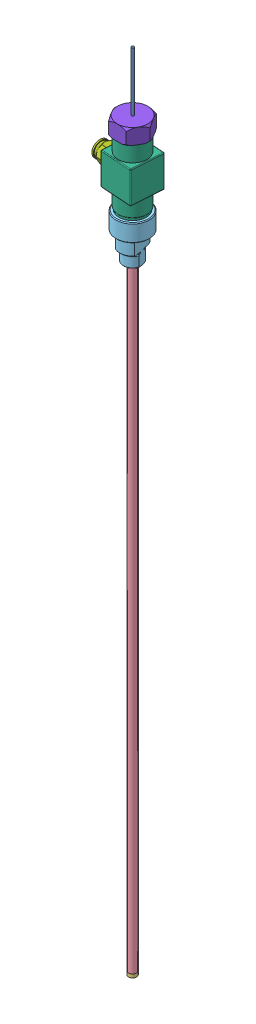
SolidWorks assembly Ensamblaje de Pipeta-Tee-Conectores, configuration Predeterminado. Lengths in mm.
Overall size (68.97 1003.7 49.84).
8 component instances, 8 part files, 12 mates.
Components (placement in the parent):
- Varilla de la pipeta-1: Varilla de la pipeta [Predeterminado] at (-128.4061 644.2501 1001.5875) size (3.17 1003.7 3.17)
- Buje interior del pico-1: Buje interior del pico [Predeterminado] at (-128.4061 -347.3121 1001.5875) x (0.891914 0 0.452205) z (-0.452205 0 0.891914) size (6 4 6)
- Pico de la Pipeta-1: Pico de la Pipeta [Predeterminado] at (-128.4061 -345.4376 1001.5875) x (0.169886 0 -0.985464) z (0.985464 0 0.169886) size (10 11 10)
- Pipeta-1: Pipeta [Predeterminado] at (-128.4061 -340.4376 1001.5875) x (0.182874 0 0.983136) z (-0.983136 0 0.182874) size (10 805 10)
- Buje Copa Superior-1: Buje Copa Superior [Predeterminado] at (-128.4061 425.5624 1001.5875) x (0.974575 0 -0.224063) z (0.224063 0 0.974575) size (41.58 56 41.58)
- Coneccion T de la Pipeta-1: Coneccion T de la Pipeta [Predeterminado] at (-128.4061 524.5624 1001.5875) x (0.997697 0 0.067828) z (-0.067828 0 0.997697) size (40 100 40)
- Conector Racor de Media G-1: Conector Racor de Media G [Predeterminado] at (-144.8924 524.5624 1000.4667) x (0.067661 -0.070187 -0.995237) z (0.997697 0 0.067828) size (26.56 20.78 32)
- Buje sello de Varilla-3: Buje sello de Varilla [Predeterminado] at (-128.4061 553.0977 1001.5875) size (48.39 37 38.11)
Mates (geometry in assembly coordinates):
- Concéntrica4: concentric aligned: cylinder of Varilla de la pipeta-1 through (-128.4061 655.5339 1001.5875) axis (0 1 0) radius 1.5875; cylinder of Buje interior del pico-1 through (-128.4061 -340.4258 1001.5875) axis (0 1 0) radius 3
- Concéntrica5: concentric aligned: cylinder of Buje interior del pico-1 through (-128.4061 -340.4258 1001.5875) axis (0 1 0) radius 3; cylinder of Pico de la Pipeta-1 through (-128.4061 -319.201 1001.5875) axis (0 1 0) radius 3
- Coincidente1: coincident anti-aligned: plane of Buje interior del pico-1 through (-127.2466 -344.4376 1002.1754) normal (0 -1 0); plane of Pico de la Pipeta-1 through (-127.8965 -344.4376 998.6311) normal (0 1 0)
- Concéntrica6: concentric anti-aligned: cylinder of Pico de la Pipeta-1 through (-128.4061 -319.201 1001.5875) axis (0 1 0) radius 4; cylinder of Pipeta-1 through (-128.4061 459.5624 1001.5875) axis (0 -1 0) radius 5
- Coincidente3: coincident anti-aligned: plane of Pico de la Pipeta-1 through (-127.5567 -340.4376 996.6602) normal (0 1 0); plane of Pipeta-1 through (-128.4061 -340.4376 1001.5875) normal (0 -1 0)
- Concéntrica7: concentric anti-aligned: cylinder of Pipeta-1 through (-128.4061 459.5624 1001.5875) axis (0 -1 0) radius 5; cylinder of Buje Copa Superior-1 through (-128.4061 475.9374 1001.5875) axis (0 1 0) radius 20.7902
- Coincidente4: coincident aligned: plane of Pipeta-1 through (-129.1376 464.5624 997.655) normal (0 1 0); plane of Buje Copa Superior-1 through (-123.2774 464.5624 1000.4084) normal (0 1 0)
- Concéntrica8: concentric anti-aligned: cylinder of Buje Copa Superior-1 through (-128.4061 475.9374 1001.5875) axis (0 1 0) radius 20.7902; cylinder of Coneccion T de la Pipeta-1 through (-128.4061 564.5624 1001.5875) axis (0 -1 0) radius 18
- Coincidente5: coincident anti-aligned: plane of Buje Copa Superior-1 through (-123.2774 464.5624 1000.4084) normal (0 1 0); plane of Coneccion T de la Pipeta-1 through (-128.4061 464.5624 1001.5875) normal (0 -1 0)
- Concéntrica10: concentric aligned: cylinder of Coneccion T de la Pipeta-1 through (-130.4015 524.5624 1001.4518) axis (-0.997697 0 -0.067828) radius 9.5; cylinder of Conector Racor de Media G-1 through (-179.7682 524.5624 998.0956) axis (-0.997697 0 -0.067828) radius 5
- Concéntrica11: concentric: cylinder of Coneccion T de la Pipeta-1 through (-128.4061 564.5624 1001.5875) axis (0 -1 0) radius 18; cylinder of Buje sello de Varilla-3 through (-128.4061 633.7899 1001.5875) axis (0 1 0) radius 17
- Coincidente6: coincident anti-aligned: plane of Coneccion T de la Pipeta-1 through (-128.4061 564.5624 1001.5875) normal (0 1 0); plane of Buje sello de Varilla-3 through (-111.4061 564.5624 1001.5875) normal (0 -1 0)
